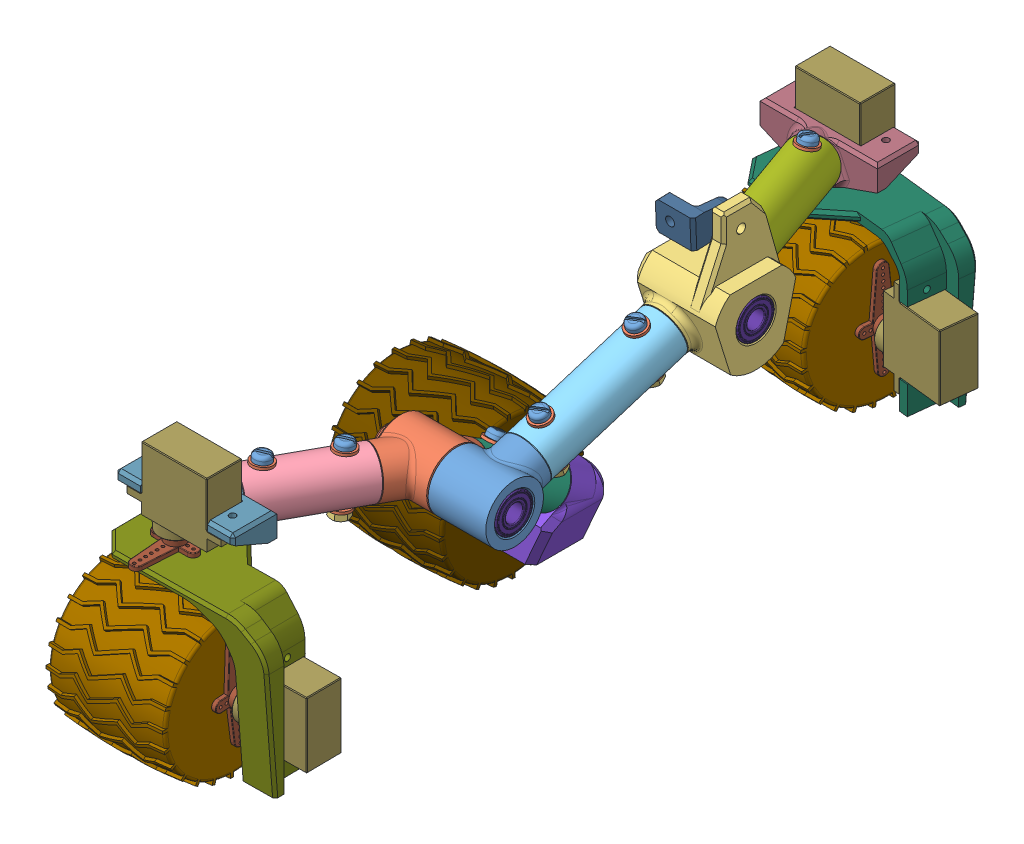
SolidWorks assembly suspensionSub-left[moving], configuration Default. Lengths in mm.
62 component instances, 21 part files, 135 mates.
Components (placement in the parent):
- bogieJointFixed-left-1: bogieJointFixed-left [Default] at (-58.6456 10.5337 84.2533) x (0 0.297904 -0.954596) z (1 0 0) size (40 20 21.53)
- bogieJointFree-left-1: bogieJointFree-left [Default] at (-79.1456 10.5337 84.2533) x (1 0 0) z (0 0.534644 0.845077) size (27.04 27.37 57.25)
- rockerJoint-left-1: rockerJoint-left [Default] at (-51.1456 34.3124 8.0574) x (1 0 0) z (0 -0.297904 0.954596) size (35.64 50.55 55.79)
- aftBogieTube-1: aftBogieTube [Default] at (-108.56 15.1077 132.4165) x (0.903071 0.263736 0.338977) z (-0.213924 0.960596 -0.177459) size (15.88 37.13 15.88)
- aftRockerTube-1: aftRockerTube [Default] at (-68.6456 15.0022 69.9343) x (1 0 0) z (0 0.954596 0.297904) size (15.88 49.82 15.88)
- foreBogieTube-1: foreBogieTube [Default] at (-89.1456 2.514 71.5771) x (0.998082 0.052308 -0.033093) z (-0.061898 0.843457 -0.533619) size (15.88 33.7 15.88)
- foreRockerTube-1: foreRockerTube [Default] at (-106.955 16.1877 -66.6715) x (0.835794 0.249633 -0.489011) z (0.320312 -0.945079 0.065011) size (15.88 70.91 15.88)
- wheelStrut-mid-right-1: wheelStrut-mid-right [Default] at (-119.2029 -30.2767 38.8726) size (23.13 36.67 28.96)
- tire-1: tire [Default] at (-113.6439 -30.2768 -79.7193) x (-0.020281 0.982539 0.184946) z (-0.994041 0 -0.109007) size (53.45 55.85 40.12)
- tire-3: tire [Default] at (-114.1463 -30.2762 146.2751) x (0.002427 0.973074 0.230481) z (-0.999945 0 0.010528) size (53.45 55.85 40.12)
- rodHinge-sus-left-1: rodHinge-sus-left [Default] at (-62.1456 34.3403 7.0424) x (0 0.33642 -0.941712) z (1 0 0) size (15.98 12.99 13)
- sg90ServoHorn-star-1: sg90ServoHorn-star [Default] at (-111.018 4.7232 -77.5199) x (0.109007 0 -0.994041) z (0.994041 0 0.109007) size (34.4 4 15.7)
- sg90ServoHorn-star-2: sg90ServoHorn-star [Default] at (-117.0162 4.7238 144.4052) x (0.010528 0 0.999945) z (-0.999945 0 0.010528) size (34.4 4 15.7)
- sg90ServoHorn-star-3: sg90ServoHorn-star [Default] at (-94.1163 -28.5447 149.0198) x (-0.000611 -0.998315 -0.058016) z (0.01051 -0.05802 0.99826) size (34.4 4 15.7)
- sg90ServoHorn-star-4: sg90ServoHorn-star [Default] at (-94.0764 -28.4129 -74.6825) x (0.001375 -0.99992 -0.012537) z (-0.108998 -0.012612 0.993962) size (34.4 4 15.7)
- sg90Servo-1: sg90Servo [Default] at (-119.8963 35.6918 140.1251) x (1 0 0) z (0 0 -1) size (32.7 29.37 12.3)
- sg90Servo-2: sg90Servo [Default] at (-63.1164 -36.0262 151.8881) x (0 1 0) z (0.010528 0 0.999945) size (32.7 29.37 12.3)
- sg90Servo-3: sg90Servo [Default] at (-63.65 -36.0268 -68.0501) x (0 1 0) z (-0.109007 0 0.994041) size (32.7 29.37 12.3)
- sg90Servo-4: sg90Servo [Default] at (-119.3939 35.6912 -85.8693) x (1 0 0) z (0 0 -1) size (32.7 29.37 12.3)
- wheelPivot-front-left-v2-1: wheelPivot-front-left-v2 [Default] at (-119.3939 35.6912 -67.5693) x (1 0 0) z (0 0 -1) size (40.7 16.47 34.17)
- wheelPivot-rear-left-v2-1: wheelPivot-rear-left-v2 [Default] at (-119.8963 35.6918 134.1251) x (-1 0 0) z (0 0 1) size (40.7 18.75 35.49)
- wheelStrut-front-left-v2-1: wheelStrut-front-left-v2 [Default] at (-64.9908 -36.0268 -55.8233) x (0 1 0) z (-0.109007 0 0.994041) size (50.75 59.16 31.22)
- wheelStrut-rear-left-v2-1: wheelStrut-rear-left-v2 [Default] at (-63.3754 -36.0262 127.2895) x (0 1 0) z (0.010528 0 0.999945) size (50.75 59.16 31.22)
- 6x13x5BearingShielded-1: 6x13x5BearingShielded [Default] at (-56.1456 34.3124 8.0574) x (0 -0.920758 0.390135) z (0 0.390135 0.920758) size (13 5 13)
- 6x13x5BearingShielded-2: 6x13x5BearingShielded [Default] at (-76.1456 34.3124 8.0574) x (0 1 0) z (0 0 1) size (13 5 13)
- 6x13x5BearingShielded-3: 6x13x5BearingShielded [Default] at (-73.6456 10.5337 84.2533) x (0 1 0) z (0 0 1) size (13 5 13)
- 6x13x5BearingShielded-4: 6x13x5BearingShielded [Default] at (-63.6456 10.5337 84.2533) x (0 -1 0) z (0 0 1) size (13 5 13)
- tire-mid-1: tire-mid [Default] at (-125.1743 -30.2767 38.8726) x (0 0.956404 0.292046) z (-1 0 0) size (53.45 55.85 40.12)
- 6x13x5BearingShielded-5: 6x13x5BearingShielded [Default] at (-110.1743 -30.2767 38.8726) x (0 -1 0) z (0 0 1) size (13 5 13)
- 6x13x5BearingShielded-6: 6x13x5BearingShielded [Default] at (-135.1743 -30.2767 38.8726) x (0 -1 0) z (0 0 1) size (13 5 13)
- pan slot head_am-1: pan slot head_am [B18.6.7M - M3 x 0.5 x 20 Slotted PHMS --20N] at (-78.6789 40.4888 -14.1636) x (0 -0.971825 0.235705) z (-0.916222 0.09444 0.389383) size (22.4 5.6 5.6)
- pan slot head_am-2: pan slot head_am [B18.6.7M - M3 x 0.5 x 20 Slotted PHMS --20N] at (-103.6106 28.6933 -62.7969) x (0 -0.971825 0.235705) z (0.226456 -0.229581 -0.946578) size (22.4 5.6 5.6)
- flat washer narrow_am-1: flat washer narrow_am [B18.22M - Plain washer, 3 mm, narrow] at (-78.6789 37.2818 -13.3857) x (0 -0.971825 0.235705) z (-0.235705 0.229064 0.944443) size (0.9 7 7)
- flat washer narrow_am-2: flat washer narrow_am [B18.22M - Plain washer, 3 mm, narrow] at (-103.6106 25.4863 -62.0191) x (0 -0.971825 0.235705) z (-0.235705 0.229064 0.944443) size (0.9 7 7)
- flat washer narrow_am-5: flat washer narrow_am [B18.22M - Plain washer, 3 mm, narrow] at (-78.6789 21.8492 -9.6427) x (0 0.971825 -0.235705) z (0.235705 0.229064 0.944443) size (0.9 7 7)
- hex nut style 1_am-1: hex nut style 1_am [B18.2.4.1M - Hex nut, Style 1,  M3 x 0.5 --D-N] at (-78.6789 18.6422 -8.8649) x (0.947171 -0.075597 -0.311692) z (0 -0.971825 0.235705) size (5.5 6.35 2.4)
- flat washer narrow_am-6: flat washer narrow_am [B18.22M - Plain washer, 3 mm, narrow] at (-103.6106 10.0537 -58.2761) x (0 0.971825 -0.235705) z (0.235705 0.229064 0.944443) size (0.9 7 7)
- hex nut style 1_am-2: hex nut style 1_am [B18.2.4.1M - Hex nut, Style 1,  M3 x 0.5 --D-N] at (-103.6106 6.8467 -57.4983) x (0.335079 0.222079 0.915644) z (0 -0.971825 0.235705) size (5.5 6.35 2.4)
- pan slot head_am-3: pan slot head_am [B18.6.7M - M3 x 0.5 x 20 Slotted PHMS --20N] at (-68.6456 38.3392 32.8843) x (0 -0.954596 -0.297904) z (-0.916222 -0.119362 0.38248) size (22.4 5.6 5.6)
- flat washer narrow_am-8: flat washer narrow_am [B18.22M - Plain washer, 3 mm, narrow] at (-68.6456 19.1709 26.9024) x (0 -0.954596 -0.297904) z (-0.235705 -0.289511 0.9277) size (0.9 7 7)
- flat washer narrow_am-9: flat washer narrow_am [B18.22M - Plain washer, 3 mm, narrow] at (-68.6456 36.0481 32.1693) x (0 0.954596 0.297904) z (0.235705 -0.289511 0.9277) size (0.9 7 7)
- hex nut style 1_am-3: hex nut style 1_am [B18.2.4.1M - Hex nut, Style 1,  M3 x 0.5 --D-N] at (-68.6456 16.8799 26.1874) x (0.947171 0.095546 -0.306166) z (0 -0.954596 -0.297904) size (5.5 6.35 2.4)
- pan slot head_am-4: pan slot head_am [B18.6.7M - M3 x 0.5 x 20 Slotted PHMS --20N] at (-68.6456 27.9662 66.1233) x (0 -0.954596 -0.297904) z (-0.916222 -0.119362 0.38248) size (22.4 5.6 5.6)
- flat washer narrow_am-10: flat washer narrow_am [B18.22M - Plain washer, 3 mm, narrow] at (-68.6456 8.7979 60.1414) x (0 -0.954596 -0.297904) z (-0.235705 -0.289511 0.9277) size (0.9 7 7)
- flat washer narrow_am-11: flat washer narrow_am [B18.22M - Plain washer, 3 mm, narrow] at (-68.6456 25.6751 65.4083) x (0 0.954596 0.297904) z (0.235705 -0.289511 0.9277) size (0.9 7 7)
- hex nut style 1_am-4: hex nut style 1_am [B18.2.4.1M - Hex nut, Style 1,  M3 x 0.5 --D-N] at (-68.6456 6.5068 59.4264) x (0.947171 0.095546 -0.306166) z (0 -0.954596 -0.297904) size (5.5 6.35 2.4)
- pan slot head_am-6: pan slot head_am [B18.6.7M - M3 x 0.5 x 20 Slotted PHMS --20N] at (-89.1456 -1.995 43.4267) x (0 -0.845077 0.534644) z (-0.916222 0.214217 0.338599) size (22.4 5.6 5.6)
- flat washer narrow_am-14: flat washer narrow_am [B18.22M - Plain washer, 3 mm, narrow] at (-89.1456 -18.9642 54.1623) x (0 -0.845077 0.534644) z (-0.235705 0.519581 0.821267) size (0.9 7 7)
- flat washer narrow_am-15: flat washer narrow_am [B18.22M - Plain washer, 3 mm, narrow] at (-89.1456 -4.0232 44.7098) x (0 0.845077 -0.534644) z (0.235705 0.519581 0.821267) size (0.9 7 7)
- hex nut style 1_am-6: hex nut style 1_am [B18.2.4.1M - Hex nut, Style 1,  M3 x 0.5 --D-N] at (-89.1456 -20.9924 55.4455) x (0.947171 -0.171476 -0.27104) z (0 -0.845077 0.534644) size (5.5 6.35 2.4)
- flat washer narrow_am-20: flat washer narrow_am [B18.22M - Plain washer, 3 mm, narrow] at (-89.1456 -8.9663 69.9653) x (0 -0.845077 0.534644) z (-0.235705 0.519581 0.821267) size (0.9 7 7)
- flat washer narrow_am-21: flat washer narrow_am [B18.22M - Plain washer, 3 mm, narrow] at (-89.1456 5.9746 60.5128) x (0 0.845077 -0.534644) z (0.235705 0.519581 0.821267) size (0.9 7 7)
- hex nut style 1_am-9: hex nut style 1_am [B18.2.4.1M - Hex nut, Style 1,  M3 x 0.5 --D-N] at (-89.1456 -10.9945 71.2484) x (0.947171 -0.171476 -0.27104) z (0 -0.845077 0.534644) size (5.5 6.35 2.4)
- pan slot head_am-9: pan slot head_am [B18.6.7M - M3 x 0.5 x 20 Slotted PHMS --20N] at (-89.1456 8.0028 59.2296) x (0 -0.845077 0.534644) z (-0.916222 0.214217 0.338599) size (22.4 5.6 5.6)
- flat washer narrow_am-22: flat washer narrow_am [B18.22M - Plain washer, 3 mm, narrow] at (-97.5251 3.7075 105.8769) x (0 -0.995521 0.094544) z (-0.195476 0.09272 0.976316) size (0.9 7 7)
- flat washer narrow_am-23: flat washer narrow_am [B18.22M - Plain washer, 3 mm, narrow] at (-97.5251 21.3083 104.2054) x (0 0.995521 -0.094544) z (0.275533 0.090884 0.956986) size (0.9 7 7)
- hex nut style 1_am-10: hex nut style 1_am [B18.2.4.1M - Hex nut, Style 1,  M3 x 0.5 --D-N] at (-97.5251 1.3182 106.1038) x (0.933157 -0.033986 -0.35786) z (0 -0.995521 0.094544) size (5.5 6.35 2.4)
- pan slot head_am-10: pan slot head_am [B18.6.7M - M3 x 0.5 x 20 Slotted PHMS --20N] at (-97.5251 23.6975 103.9785) x (0 -0.995521 0.094544) z (-0.898941 0.041417 0.436108) size (22.4 5.6 5.6)
- flat washer narrow_am-24: flat washer narrow_am [B18.22M - Plain washer, 3 mm, narrow] at (-105.7668 5.6492 126.323) x (0 -0.995521 0.094544) z (-0.195476 0.09272 0.976316) size (0.9 7 7)
- flat washer narrow_am-25: flat washer narrow_am [B18.22M - Plain washer, 3 mm, narrow] at (-105.7668 23.25 124.6514) x (0 0.995521 -0.094544) z (0.275533 0.090884 0.956986) size (0.9 7 7)
- hex nut style 1_am-11: hex nut style 1_am [B18.2.4.1M - Hex nut, Style 1,  M3 x 0.5 --D-N] at (-105.7668 3.26 126.5499) x (0.933157 -0.033986 -0.35786) z (0 -0.995521 0.094544) size (5.5 6.35 2.4)
- pan slot head_am-11: pan slot head_am [B18.6.7M - M3 x 0.5 x 20 Slotted PHMS --20N] at (-105.7668 25.6393 124.4245) x (0 -0.995521 0.094544) z (-0.898941 0.041417 0.436108) size (22.4 5.6 5.6)
Mates (geometry in assembly coordinates):
- Parallel1: parallel aligned: plane of rockerJoint-left-1 through (-81.1466 46.3124 8.0574) normal (0 1 0); plane of assembly through (0 0 0) normal (0 1 0)
- Concentric3: concentric aligned: line of rockerJoint-left-1 through (-68.6456 34.3124 8.0574) axis (-0.445925 -0.210972 -0.869851); cylinder of foreRockerTube-1 through (-75.3345 31.1478 -4.9903) axis (-0.445925 -0.210972 -0.869851) radius 7.94
- Coincident4: coincident anti-aligned: plane of rockerJoint-left-1 through (-75.3345 31.1478 -4.9903) normal (-0.445925 -0.210972 -0.869851); plane of foreRockerTube-1 through (-75.3345 31.1478 -4.9903) normal (0.445925 0.210972 0.869851)
- Concentric4: concentric anti-aligned: line of rockerJoint-left-1 through (-68.6456 9.9222 86.2125) axis (0 0.297904 -0.954596); cylinder of aftRockerTube-1 through (-68.6456 29.8438 22.3764) axis (0 -0.297904 0.954596) radius 7.94
- Coincident5: coincident anti-aligned: plane of rockerJoint-left-1 through (-68.6456 29.8438 22.3764) normal (0 -0.297904 0.954596); plane of aftRockerTube-1 through (-68.6456 29.8438 22.3764) normal (0 0.297904 -0.954596)
- Concentric5: concentric aligned: line of bogieJointFixed-left-1 through (-68.6456 15.0022 69.9343) axis (0 -0.297904 0.954596); cylinder of aftRockerTube-1 through (-68.6456 29.8438 22.3764) axis (0 -0.297904 0.954596) radius 7.94
- Coincident6: coincident anti-aligned: plane of bogieJointFixed-left-1 through (-68.6456 15.0022 69.9343) normal (0 0.297904 -0.954596); plane of aftRockerTube-1 through (-68.6456 15.0022 69.9343) normal (0 -0.297904 0.954596)
- Concentric6: concentric anti-aligned: line of bogieJointFree-left-1 through (-89.1456 10.5337 84.2533) axis (0 -0.534644 -0.845077); cylinder of foreBogieTube-1 through (-89.1456 -15.5035 43.098) axis (0 0.534644 0.845077) radius 7.94
- Coincident9: coincident anti-aligned: plane of bogieJointFree-left-1 through (-89.1456 2.514 71.5771) normal (0 -0.534644 -0.845077); plane of foreBogieTube-1 through (-89.1456 2.514 71.5771) normal (0 0.534644 0.845077)
- Concentric8: concentric anti-aligned: line of bogieJointFree-left-1 through (-114.1456 16.4237 146.2733) axis (0.372423 -0.087743 -0.923906); cylinder of aftBogieTube-1 through (-94.732 11.8498 98.1119) axis (-0.372423 0.087743 0.923906) radius 7.94
- Coincident11: coincident anti-aligned: plane of bogieJointFree-left-1 through (-94.732 11.8498 98.1119) normal (-0.372423 0.087743 0.923906); plane of aftBogieTube-1 through (-94.732 11.8498 98.1119) normal (0.372423 -0.087743 -0.923906)
- Concentric12: concentric anti-aligned: cylinder of foreBogieTube-1 through (-89.1456 -15.5035 43.098) axis (0 0.534644 0.845077) radius 7.94; line of wheelStrut-mid-right-1 through (-89.1456 10.5333 84.2526) axis (0 -0.534644 -0.845077)
- Coincident14: coincident anti-aligned: plane of foreBogieTube-1 through (-89.1456 -15.5035 43.098) normal (0 -0.534644 -0.845077); plane of wheelStrut-mid-right-1 through (-89.1456 -15.5035 43.098) normal (0 0.534644 0.845077)
- Distance6: distance = 1 mm anti-aligned: plane of rockerJoint-left-1 through (-61.1456 40.2303 22.2025) normal (-1 0 0); plane of rodHinge-sus-left-1 through (-62.1456 34.3403 7.0424) normal (1 0 0)
- Concentric18: concentric anti-aligned: cylinder of rockerJoint-left-1 through (-51.1446 59.3124 8.2384) axis (-1 0 0) radius 1.55; cylinder of rodHinge-sus-left-1 through (-65.1456 59.3124 8.2384) axis (1 0 0) radius 1.55
- Concentric20: concentric aligned: cylinder of foreRockerTube-1 through (-75.3345 31.1478 -4.9903) axis (-0.445925 -0.210972 -0.869851) radius 7.94; cylinder of wheelPivot-front-left-v2-1 through (-106.955 16.1877 -66.6715) axis (-0.445925 -0.210972 -0.869851) radius 7.94
- Coincident46: coincident anti-aligned: plane of foreRockerTube-1 through (-106.955 16.1877 -66.6715) normal (-0.445925 -0.210972 -0.869851); plane of wheelPivot-front-left-v2-1 through (-106.955 16.1877 -66.6715) normal (0.445925 0.210972 0.869851)
- Parallel2: parallel aligned: plane of rockerJoint-left-1 through (-81.1466 46.3124 8.0574) normal (0 1 0); plane of wheelPivot-front-left-v2-1 through (-119.3939 23.0662 -70.5693) normal (0 1 0)
- Coincident48: coincident aligned: line of sg90Servo-4 through (-96.4439 20.0662 -85.6193) axis (0 0 1); line of wheelPivot-front-left-v2-1 through (-96.4439 20.0662 -85.8693) axis (0 0 1)
- Coincident49: coincident anti-aligned: line of sg90Servo-4 through (-119.6439 20.0662 -73.8193) axis (0 0 -1); line of wheelPivot-front-left-v2-1 through (-119.6439 20.0662 -85.8693) axis (0 0 1)
- Coincident50: coincident anti-aligned: plane of sg90Servo-4 through (-119.3939 13.4662 -73.5693) normal (0 0 1); plane of wheelPivot-front-left-v2-1 through (-119.3939 35.6912 -73.5693) normal (0 0 -1)
- Concentric21: concentric aligned: cylinder of aftBogieTube-1 through (-94.732 11.8498 98.1119) axis (-0.372423 0.087743 0.923906) radius 7.94; cylinder of wheelPivot-rear-left-v2-1 through (-108.56 15.1077 132.4165) axis (-0.372423 0.087743 0.923906) radius 7.94
- Coincident51: coincident anti-aligned: plane of aftBogieTube-1 through (-108.56 15.1077 132.4165) normal (-0.372423 0.087743 0.923906); plane of wheelPivot-rear-left-v2-1 through (-108.56 15.1077 132.4165) normal (0.372423 -0.087743 -0.923906)
- Coincident53: coincident aligned: line of sg90Servo-1 through (-120.1463 20.0668 152.1751) axis (0 0 -1); line of wheelPivot-rear-left-v2-1 through (-120.1463 20.0668 152.4251) axis (0 0 -1)
- Coincident54: coincident anti-aligned: line of sg90Servo-1 through (-96.9463 20.0668 140.3751) axis (0 0 1); line of wheelPivot-rear-left-v2-1 through (-96.9463 20.0668 152.4251) axis (0 0 -1)
- Coincident55: coincident anti-aligned: plane of sg90Servo-1 through (-119.8963 13.4668 140.1251) normal (0 0 -1); plane of wheelPivot-rear-left-v2-1 through (-119.8963 35.6918 140.1251) normal (0 0 1)
- Coincident56: coincident anti-aligned: plane of sg90ServoHorn-star-1 through (-111.018 4.7232 -77.5199) normal (0 -1 0); plane of wheelStrut-front-left-v2-1 through (-61.5462 4.7232 -87.235) normal (0 1 0)
- Concentric22: concentric aligned: cylinder of sg90ServoHorn-star-1 through (-113.6439 4.7222 -79.7193) axis (0 1 0) radius 1.2; cylinder of wheelStrut-front-left-v2-1 through (-113.6439 -46.0279 -79.7193) axis (0 1 0) radius 2.4
- Coincident58: coincident anti-aligned: plane of sg90ServoHorn-star-2 through (-117.0162 4.7238 144.4052) normal (0 -1 0); plane of wheelStrut-rear-left-v2-1 through (-63.0427 4.7238 158.8878) normal (0 1 0)
- Concentric23: concentric aligned: cylinder of sg90ServoHorn-star-2 through (-114.1463 4.7228 146.2751) axis (0 1 0) radius 1.2; cylinder of wheelStrut-rear-left-v2-1 through (-114.1463 -46.0272 146.2751) axis (0 1 0) radius 2.4
- Concentric24: concentric aligned: cylinder of sg90ServoHorn-star-1 through (-113.6439 6.3232 -79.7193) axis (0 1 0) radius 2.4; cylinder of sg90Servo-4 through (-113.6439 6.3232 -79.7193) axis (0 1 0) radius 1.984
- Coincident60: coincident anti-aligned: plane of sg90ServoHorn-star-1 through (-113.6439 6.3232 -79.7193) normal (0 1 0); plane of sg90Servo-4 through (-113.6439 6.3232 -79.7193) normal (0 -1 0)
- Concentric25: concentric aligned: cylinder of sg90ServoHorn-star-2 through (-114.1463 6.3238 146.2751) axis (0 1 0) radius 2.4; cylinder of sg90Servo-1 through (-114.1463 6.3238 146.2751) axis (0 1 0) radius 1.984
- Coincident61: coincident anti-aligned: plane of sg90ServoHorn-star-2 through (-114.1463 6.3238 146.2751) normal (0 1 0); plane of sg90Servo-1 through (-114.1463 6.3238 146.2751) normal (0 -1 0)
- Coincident63: coincident anti-aligned: plane of tire-3 through (-94.0892 -6.9248 151.5955) normal (0.999945 0 -0.010528); plane of sg90ServoHorn-star-3 through (-94.1163 -28.5447 149.0198) normal (-0.999945 0 0.010528)
- Concentric26: concentric anti-aligned: line of tire-3 through (-92.1476 -30.2762 146.0435) axis (-0.999945 0 0.010528); cylinder of sg90ServoHorn-star-3 through (-94.1485 -30.2762 146.0645) axis (0.999945 0 -0.010528) radius 1.2
- Coincident64: coincident anti-aligned: line of sg90Servo-2 through (-78.7432 -13.0762 151.8027) axis (-0.010528 0 -0.999945); line of wheelStrut-rear-left-v2-1 through (-78.8701 -13.0762 139.7533) axis (0.010528 0 0.999945)
- Coincident65: coincident aligned: line of sg90Servo-2 through (-78.8674 -36.2762 140.0033) axis (0.010528 0 0.999945); line of wheelStrut-rear-left-v2-1 through (-78.8701 -36.2762 139.7533) axis (0.010528 0 0.999945)
- Coincident66: coincident anti-aligned: plane of sg90Servo-2 through (-85.3402 -36.0262 152.1221) normal (0.010528 0 0.999945); plane of wheelStrut-rear-left-v2-1 through (-63.1164 -36.0262 151.8881) normal (-0.010528 0 -0.999945)
- Concentric28: concentric aligned: cylinder of sg90ServoHorn-star-3 through (-92.5475 -30.2762 146.0477) axis (0.999945 0 -0.010528) radius 2.4; cylinder of sg90Servo-2 through (-92.5475 -30.2762 146.0477) axis (0.999945 0 -0.010528) radius 1.984
- Coincident67: coincident anti-aligned: plane of sg90ServoHorn-star-3 through (-92.5475 -30.2762 146.0477) normal (0.999945 0 -0.010528); plane of sg90Servo-2 through (-92.5475 -30.2762 146.0477) normal (-0.999945 0 0.010528)
- Coincident68: coincident anti-aligned: plane of tire-1 through (-94.2498 -6.6984 -73.1009) normal (0.994041 0 0.109007); plane of sg90ServoHorn-star-4 through (-94.0764 -28.4129 -74.6825) normal (-0.994041 0 -0.109007)
- Concentric30: concentric anti-aligned: line of tire-1 through (-91.775 -30.2768 -77.3211) axis (-0.994041 0 -0.109007); cylinder of sg90ServoHorn-star-4 through (-93.7641 -30.2768 -77.5392) axis (0.994041 0 0.109007) radius 1.2
- Coincident69: coincident aligned: line of sg90Servo-3 through (-79.1547 -13.0768 -70.0018) axis (0.109007 0 -0.994041); line of wheelStrut-front-left-v2-1 through (-79.1819 -13.0768 -69.7533) axis (0.109007 0 -0.994041)
- Coincident70: coincident anti-aligned: line of sg90Servo-3 through (-77.8684 -36.2768 -81.7315) axis (-0.109007 0 0.994041); line of wheelStrut-front-left-v2-1 through (-79.1819 -36.2768 -69.7533) axis (0.109007 0 -0.994041)
- Coincident71: coincident anti-aligned: plane of sg90Servo-3 through (-84.4018 -36.0268 -82.6994) normal (0.109007 0 -0.994041); plane of wheelStrut-front-left-v2-1 through (-62.3092 -36.0268 -80.2768) normal (-0.109007 0 0.994041)
- Concentric33: concentric aligned: cylinder of sg90ServoHorn-star-4 through (-92.1726 -30.2768 -77.3647) axis (0.994041 0 0.109007) radius 2.4; cylinder of sg90Servo-3 through (-92.1726 -30.2768 -77.3647) axis (0.994041 0 0.109007) radius 1.984
- Coincident72: coincident anti-aligned: plane of sg90ServoHorn-star-4 through (-92.1726 -30.2768 -77.3647) normal (0.994041 0 0.109007); plane of sg90Servo-3 through (-92.1726 -30.2768 -77.3647) normal (-0.994041 0 -0.109007)
- Concentric34: concentric anti-aligned: cylinder of rockerJoint-left-1 through (-75.1456 34.3124 8.0574) axis (-1 0 0) radius 6.5; cylinder of 6x13x5BearingShielded-2 through (-81.1456 34.3124 8.0574) axis (1 0 0) radius 6.5
- Coincident73: coincident aligned: plane of rockerJoint-left-1 through (-81.1456 34.3124 8.0574) normal (-1 0 0); plane of 6x13x5BearingShielded-2 through (-81.1456 34.3124 8.0574) normal (-1 0 0)
- Concentric35: concentric anti-aligned: cylinder of rockerJoint-left-1 through (-57.1456 34.3124 8.0574) axis (1 0 0) radius 6.5; cylinder of 6x13x5BearingShielded-1 through (-51.1456 34.3124 8.0574) axis (-1 0 0) radius 6.5
- Coincident74: coincident aligned: plane of rockerJoint-left-1 through (-51.1456 34.3124 8.0574) normal (1 0 0); plane of 6x13x5BearingShielded-1 through (-51.1456 34.3124 8.0574) normal (1 0 0)
- Concentric37: concentric anti-aligned: cylinder of bogieJointFixed-left-1 through (-64.6456 10.5337 84.2533) axis (1 0 0) radius 6.5; cylinder of 6x13x5BearingShielded-4 through (-58.6456 10.5337 84.2533) axis (-1 0 0) radius 6.5
- Coincident75: coincident aligned: plane of bogieJointFixed-left-1 through (-58.6456 10.5337 84.2533) normal (1 0 0); plane of 6x13x5BearingShielded-4 through (-58.6456 10.5337 84.2533) normal (1 0 0)
- Concentric38: concentric anti-aligned: cylinder of bogieJointFixed-left-1 through (-72.6456 10.5337 84.2533) axis (-1 0 0) radius 6.5; cylinder of 6x13x5BearingShielded-3 through (-78.6456 10.5337 84.2533) axis (1 0 0) radius 6.5
- Coincident76: coincident aligned: plane of bogieJointFixed-left-1 through (-78.6456 10.5337 84.2533) normal (-1 0 0); plane of 6x13x5BearingShielded-3 through (-78.6456 10.5337 84.2533) normal (-1 0 0)
- Concentric39: concentric aligned: cylinder of bogieJointFixed-left-1 through (-78.6456 10.5337 84.2533) axis (1 0 0) radius 10; cylinder of bogieJointFree-left-1 through (-99.1456 10.5337 84.2533) axis (1 0 0) radius 10
- Distance7: distance = 0.5 mm anti-aligned: plane of bogieJointFree-left-1 through (-79.1456 10.5337 84.2533) normal (1 0 0); plane of bogieJointFixed-left-1 through (-78.6456 10.5337 84.2533) normal (-1 0 0)
- Concentric40: concentric aligned: cylinder of wheelStrut-mid-right-1 through (-76.2571 -30.2767 38.8726) axis (-1 0 0) radius 3; cylinder of tire-mid-1 through (-105.1146 -30.2767 38.8726) axis (-1 0 0) radius 3.75
- Distance8: distance = 1 mm anti-aligned: plane of tire-mid-1 through (-105.1743 -7.3254 45.881) normal (1 0 0); plane of wheelStrut-mid-right-1 through (-104.1743 -30.2767 48.8726) normal (-1 0 0)
- Concentric41: concentric anti-aligned: cylinder of tire-mid-1 through (-111.1743 -30.2767 38.8726) axis (1 0 0) radius 6.5; cylinder of 6x13x5BearingShielded-5 through (-105.1743 -30.2767 38.8726) axis (-1 0 0) radius 6.5
- Coincident79: coincident aligned: plane of tire-mid-1 through (-105.1743 -7.3254 45.881) normal (1 0 0); plane of 6x13x5BearingShielded-5 through (-105.1743 -30.2767 38.8726) normal (1 0 0)
- Concentric42: concentric aligned: cylinder of tire-mid-1 through (-129.1743 -30.2767 38.8726) axis (-1 0 0) radius 6.5; cylinder of 6x13x5BearingShielded-6 through (-130.1743 -30.2767 38.8726) axis (-1 0 0) radius 6.5
- Coincident80: coincident aligned: plane of tire-mid-1 through (-135.1743 -30.2767 38.8726) normal (-1 0 0); plane of 6x13x5BearingShielded-6 through (-135.1743 -30.2767 38.8726) normal (-1 0 0)
- Concentric45: concentric aligned: cylinder of tire-3 through (-104.5519 -15.3014 147.0444) axis (0.999945 0 -0.010528) radius 0.5; cylinder of sg90ServoHorn-star-3 through (-94.1393 -15.3014 146.9348) axis (0.999945 0 -0.010528) radius 0.5
- Concentric46: concentric aligned: cylinder of tire-1 through (-104.1359 -15.278 -78.4863) axis (0.994041 0 0.109007) radius 0.5; cylinder of sg90ServoHorn-star-4 through (-93.7847 -15.278 -77.3512) axis (0.994041 0 0.109007) radius 0.5
- Concentric47: concentric aligned: cylinder of sg90ServoHorn-star-2 through (-114.2411 4.7228 137.2756) axis (0 1 0) radius 0.5; cylinder of wheelStrut-rear-left-v2-1 through (-114.2411 -46.0272 137.2756) axis (0 1 0) radius 0.5
- Concentric48: concentric aligned: cylinder of sg90ServoHorn-star-1 through (-114.625 4.7222 -70.7729) axis (0 1 0) radius 0.5; cylinder of wheelStrut-front-left-v2-1 through (-114.625 -46.0279 -70.7729) axis (0 1 0) radius 0.5
- Concentric49: concentric anti-aligned: cylinder of rockerJoint-left-1 through (-78.6789 -0.8192 -4.1448) axis (0 0.971825 -0.235705) radius 1.55; cylinder of foreRockerTube-1 through (-78.6789 39.5321 -13.9315) axis (0 -0.971825 0.235705) radius 1.55
- Concentric52: concentric anti-aligned: cylinder of rockerJoint-left-1 through (-68.6456 9.987 24.0363) axis (0 0.954596 0.297904) radius 1.55; cylinder of aftRockerTube-1 through (-68.6458 35.189 31.9012) axis (0 -0.954596 -0.297904) radius 1.55
- Concentric71: concentric aligned: cylinder of pan slot head_am-1 through (-78.6789 65.1731 -20.1504) axis (0 0.971825 -0.235705) radius 1.5; cylinder of flat washer narrow_am-1 through (-78.6789 71.2228 -21.6177) axis (0 0.971825 -0.235705) radius 1.84
- Concentric721: concentric anti-aligned: cylinder of foreRockerTube-1 through (-78.6789 39.5321 -13.9315) axis (0 -0.971825 0.235705) radius 1.55; cylinder of pan slot head_am-1 through (-78.6789 65.1731 -20.1504) axis (0 0.971825 -0.235705) radius 1.5
- Coincident831: coincident anti-aligned: plane of pan slot head_am-1 through (-78.0779 38.4804 -12.2623) normal (0 -0.971825 0.235705); plane of flat washer narrow_am-1 through (-75.2775 38.3509 -12.7961) normal (0 0.971825 -0.235705)
- Concentric73: concentric aligned: cylinder of pan slot head_am-2 through (-103.6106 53.3777 -68.7838) axis (0 0.971825 -0.235705) radius 1.5; cylinder of flat washer narrow_am-2 through (-103.6106 59.4273 -70.2511) axis (0 0.971825 -0.235705) radius 1.84
- Concentric741: concentric anti-aligned: cylinder of foreRockerTube-1 through (-103.6106 27.7367 -62.5649) axis (0 -0.971825 0.235705) radius 1.55; cylinder of pan slot head_am-2 through (-103.6106 53.3777 -68.7838) axis (0 0.971825 -0.235705) radius 1.5
- Coincident841: coincident anti-aligned: plane of pan slot head_am-2 through (-105.0716 26.2809 -62.5614) normal (0 -0.971825 0.235705); plane of flat washer narrow_am-2 through (-100.2092 26.5554 -61.4295) normal (0 0.971825 -0.235705)
- Concentric77: concentric anti-aligned: cylinder of pan slot head_am-1 through (-78.6789 65.1731 -20.1504) axis (0 0.971825 -0.235705) radius 1.5; cylinder of flat washer narrow_am-5 through (-78.6789 -12.0918 -1.4108) axis (0 -0.971825 0.235705) radius 1.84
- Concentric78: concentric anti-aligned: cylinder of pan slot head_am-1 through (-78.6789 65.1731 -20.1504) axis (0 0.971825 -0.235705) radius 1.5; cylinder of hex nut style 1_am-1 through (-78.6789 42.9742 -14.7664) axis (0 -0.971825 0.235705) radius 1.5
- Coincident85: coincident anti-aligned: plane of flat washer narrow_am-5 through (-82.0803 21.169 -8.6289) normal (0 -0.971825 0.235705); plane of hex nut style 1_am-1 through (-77.6605 21.6835 -6.5077) normal (0 0.971825 -0.235705)
- Concentric79: concentric anti-aligned: cylinder of pan slot head_am-2 through (-103.6106 53.3777 -68.7838) axis (0 0.971825 -0.235705) radius 1.5; cylinder of flat washer narrow_am-6 through (-103.6106 -23.8872 -50.0441) axis (0 -0.971825 0.235705) radius 1.84
- Concentric80: concentric anti-aligned: cylinder of pan slot head_am-2 through (-103.6106 53.3777 -68.7838) axis (0 0.971825 -0.235705) radius 1.5; cylinder of hex nut style 1_am-2 through (-103.6106 31.1788 -63.3998) axis (0 -0.971825 0.235705) radius 1.5
- Coincident86: coincident anti-aligned: plane of flat washer narrow_am-6 through (-107.012 9.3736 -57.2623) normal (0 -0.971825 0.235705); plane of hex nut style 1_am-2 through (-106.6025 9.4299 -57.03) normal (0 0.971825 -0.235705)
- Tangent1: tangent anti-aligned: cylinder of foreRockerTube-1 through (-75.3345 31.1478 -4.9903) axis (-0.445925 -0.210972 -0.869851) radius 7.94; plane of flat washer narrow_am-2 through (-101.8224 25.5885 -61.5976) normal (0 -0.971825 0.235705)
- Tangent2: tangent anti-aligned: cylinder of foreRockerTube-1 through (-75.3345 31.1478 -4.9903) axis (-0.445925 -0.210972 -0.869851) radius 7.94; plane of flat washer narrow_am-6 through (-105.3988 10.156 -57.8547) normal (0 0.971825 -0.235705)
- Tangent3: tangent anti-aligned: cylinder of foreRockerTube-1 through (-75.3345 31.1478 -4.9903) axis (-0.445925 -0.210972 -0.869851) radius 7.94; plane of flat washer narrow_am-1 through (-76.8908 37.384 -12.9643) normal (0 -0.971825 0.235705)
- Tangent4: tangent anti-aligned: cylinder of foreRockerTube-1 through (-75.3345 31.1478 -4.9903) axis (-0.445925 -0.210972 -0.869851) radius 7.94; plane of flat washer narrow_am-5 through (-80.4671 21.9514 -9.2213) normal (0 0.971825 -0.235705)
- Concentric83: concentric anti-aligned: cylinder of pan slot head_am-3 through (-68.6456 62.5859 40.451) axis (0 0.954596 0.297904) radius 1.5; cylinder of flat washer narrow_am-9 through (-68.6456 2.7089 21.765) axis (0 -0.954596 -0.297904) radius 1.84
- Coincident90: coincident anti-aligned: plane of pan slot head_am-3 through (-68.0446 35.6387 33.4812) normal (0 -0.954596 -0.297904); plane of flat washer narrow_am-9 through (-70.4338 35.9189 32.5833) normal (0 0.954596 0.297904)
- Concentric84: concentric aligned: cylinder of pan slot head_am-3 through (-68.6456 62.5859 40.451) axis (0 0.954596 0.297904) radius 1.5; cylinder of flat washer narrow_am-8 through (-68.6456 52.5102 37.3067) axis (0 0.954596 0.297904) radius 1.84
- Concentric85: concentric anti-aligned: cylinder of pan slot head_am-3 through (-68.6456 62.5859 40.451) axis (0 0.954596 0.297904) radius 1.5; cylinder of hex nut style 1_am-3 through (-68.6456 19.1709 26.9024) axis (0 -0.954596 -0.297904) radius 1.25
- Coincident91: coincident anti-aligned: plane of flat washer narrow_am-8 through (-66.8575 19.0417 27.3164) normal (0 -0.954596 -0.297904); plane of hex nut style 1_am-3 through (-67.6272 18.2749 29.7735) normal (0 0.954596 0.297904)
- Concentric86: concentric aligned: cylinder of rockerJoint-left-1 through (-68.6456 9.987 24.0363) axis (0 0.954596 0.297904) radius 1.55; cylinder of pan slot head_am-3 through (-68.6456 62.5859 40.451) axis (0 0.954596 0.297904) radius 1.5
- Tangent5: tangent anti-aligned: cylinder of aftRockerTube-1 through (-68.6456 29.8438 22.3764) axis (0 -0.297904 0.954596) radius 7.94; plane of flat washer narrow_am-9 through (-72.047 34.9432 32.6887) normal (0 -0.954596 -0.297904)
- Tangent6: tangent anti-aligned: cylinder of aftRockerTube-1 through (-68.6456 29.8438 22.3764) axis (0 -0.297904 0.954596) radius 7.94; plane of flat washer narrow_am-8 through (-65.2442 19.7843 27.958) normal (0 0.954596 0.297904)
- Concentric742: concentric anti-aligned: cylinder of bogieJointFixed-left-1 through (-68.6456 7.6896 59.7955) axis (0 0.954596 0.297904) radius 1.55; cylinder of aftRockerTube-1 through (-68.6458 24.816 65.1402) axis (0 -0.954596 -0.297904) radius 1.55
- Concentric743: concentric anti-aligned: cylinder of pan slot head_am-4 through (-68.6456 52.2129 73.6901) axis (0 0.954596 0.297904) radius 1.5; cylinder of flat washer narrow_am-11 through (-68.6456 -7.6641 55.004) axis (0 -0.954596 -0.297904) radius 1.84
- Coincident842: coincident anti-aligned: plane of pan slot head_am-4 through (-68.0446 25.2657 66.7203) normal (0 -0.954596 -0.297904); plane of flat washer narrow_am-11 through (-70.4338 25.5459 65.8223) normal (0 0.954596 0.297904)
- Concentric744: concentric aligned: cylinder of pan slot head_am-4 through (-68.6456 52.2129 73.6901) axis (0 0.954596 0.297904) radius 1.5; cylinder of flat washer narrow_am-10 through (-68.6456 42.1371 70.5457) axis (0 0.954596 0.297904) radius 1.84
- Concentric745: concentric anti-aligned: cylinder of pan slot head_am-4 through (-68.6456 52.2129 73.6901) axis (0 0.954596 0.297904) radius 1.5; cylinder of hex nut style 1_am-4 through (-68.6456 8.7979 60.1414) axis (0 -0.954596 -0.297904) radius 1.25
- Coincident843: coincident anti-aligned: plane of flat washer narrow_am-10 through (-66.8575 8.6687 60.5554) normal (0 -0.954596 -0.297904); plane of hex nut style 1_am-4 through (-67.6272 7.9019 63.0125) normal (0 0.954596 0.297904)
- Tangent7: tangent anti-aligned: cylinder of aftRockerTube-1 through (-68.6456 29.8438 22.3764) axis (0 -0.297904 0.954596) radius 7.94; plane of flat washer narrow_am-11 through (-72.047 24.5702 65.9277) normal (0 -0.954596 -0.297904)
- Tangent8: tangent anti-aligned: cylinder of aftRockerTube-1 through (-68.6456 29.8438 22.3764) axis (0 -0.297904 0.954596) radius 7.94; plane of flat washer narrow_am-10 through (-65.2442 9.4112 61.197) normal (0 0.954596 0.297904)
- Concentric746: concentric aligned: cylinder of bogieJointFixed-left-1 through (-68.6456 7.6896 59.7955) axis (0 0.954596 0.297904) radius 1.55; cylinder of pan slot head_am-4 through (-68.6456 52.2129 73.6901) axis (0 0.954596 0.297904) radius 1.5
- Concentric750: concentric anti-aligned: cylinder of pan slot head_am-6 through (-89.1456 19.4699 29.8467) axis (0 0.845077 -0.534644) radius 1.5; cylinder of flat washer narrow_am-15 through (-89.1456 -33.5375 63.3823) axis (0 -0.845077 0.534644) radius 1.84
- Coincident846: coincident anti-aligned: plane of pan slot head_am-6 through (-88.5446 -3.2884 45.8712) normal (0 -0.845077 0.534644); plane of flat washer narrow_am-15 through (-90.9338 -3.7913 45.0763) normal (0 0.845077 -0.534644)
- Concentric751: concentric aligned: cylinder of pan slot head_am-6 through (-89.1456 19.4699 29.8467) axis (0 0.845077 -0.534644) radius 1.5; cylinder of flat washer narrow_am-14 through (-89.1456 10.5501 35.4899) axis (0 0.845077 -0.534644) radius 1.84
- Concentric752: concentric anti-aligned: cylinder of pan slot head_am-6 through (-89.1456 19.4699 29.8467) axis (0 0.845077 -0.534644) radius 1.5; cylinder of hex nut style 1_am-6 through (-89.1456 -18.9642 54.1623) axis (0 -0.845077 0.534644) radius 1.25
- Coincident847: coincident anti-aligned: plane of flat washer narrow_am-14 through (-87.3575 -18.7323 54.5288) normal (0 -0.845077 0.534644); plane of hex nut style 1_am-6 through (-88.1272 -17.3561 56.7041) normal (0 0.845077 -0.534644)
- Tangent11: tangent anti-aligned: cylinder of foreBogieTube-1 through (-89.1456 -15.5035 43.098) axis (0 0.534644 0.845077) radius 7.94; plane of flat washer narrow_am-15 through (-92.547 -4.3427 45.8882) normal (0 -0.845077 0.534644)
- Tangent12: tangent anti-aligned: cylinder of foreBogieTube-1 through (-89.1456 -15.5035 43.098) axis (0 0.534644 0.845077) radius 7.94; plane of flat washer narrow_am-14 through (-85.7442 -17.7625 54.3783) normal (0 0.845077 -0.534644)
- Concentric753: concentric aligned: cylinder of wheelStrut-mid-right-1 through (-89.1456 -35.8441 64.8415) axis (0 0.845077 -0.534644) radius 1.55; cylinder of pan slot head_am-6 through (-89.1456 19.4699 29.8467) axis (0 0.845077 -0.534644) radius 1.5
- Concentric762: concentric anti-aligned: cylinder of flat washer narrow_am-21 through (-89.1456 -23.5397 79.1852) axis (0 -0.845077 0.534644) radius 1.84; cylinder of pan slot head_am-9 through (-89.1456 29.4678 45.6497) axis (0 0.845077 -0.534644) radius 1.5
- Coincident855: coincident anti-aligned: plane of flat washer narrow_am-21 through (-90.9338 6.2065 60.8793) normal (0 0.845077 -0.534644); plane of pan slot head_am-9 through (-88.5446 6.7094 61.6742) normal (0 -0.845077 0.534644)
- Concentric763: concentric aligned: cylinder of flat washer narrow_am-20 through (-89.1456 20.548 51.2928) axis (0 0.845077 -0.534644) radius 1.84; cylinder of pan slot head_am-9 through (-89.1456 29.4678 45.6497) axis (0 0.845077 -0.534644) radius 1.5
- Concentric764: concentric anti-aligned: cylinder of hex nut style 1_am-9 through (-89.1456 -8.9663 69.9653) axis (0 -0.845077 0.534644) radius 1.25; cylinder of pan slot head_am-9 through (-89.1456 29.4678 45.6497) axis (0 0.845077 -0.534644) radius 1.5
- Coincident856: coincident anti-aligned: plane of flat washer narrow_am-20 through (-87.3575 -8.7344 70.3318) normal (0 -0.845077 0.534644); plane of hex nut style 1_am-9 through (-88.1272 -7.3583 72.507) normal (0 0.845077 -0.534644)
- Tangent17: tangent anti-aligned: cylinder of foreBogieTube-1 through (-89.1456 -15.5035 43.098) axis (0 0.534644 0.845077) radius 7.94; plane of flat washer narrow_am-20 through (-85.7442 -7.7647 70.1813) normal (0 0.845077 -0.534644)
- Tangent19: tangent anti-aligned: cylinder of foreBogieTube-1 through (-89.1456 -15.5035 43.098) axis (0 0.534644 0.845077) radius 7.94; plane of flat washer narrow_am-21 through (-92.547 5.6551 61.6911) normal (0 -0.845077 0.534644)
- Concentric766: concentric aligned: cylinder of bogieJointFree-left-1 through (-89.1456 -16.1798 74.529) axis (0 0.845077 -0.534644) radius 1.55; cylinder of pan slot head_am-9 through (-89.1456 29.4678 45.6497) axis (0 0.845077 -0.534644) radius 1.5
- Concentric767: concentric anti-aligned: cylinder of flat washer narrow_am-23 through (-97.5251 -13.4603 107.5073) axis (0 -0.995521 0.094544) radius 1.84; cylinder of pan slot head_am-10 through (-97.5251 48.9837 101.5771) axis (0 0.995521 -0.094544) radius 1.5
- Coincident857: coincident anti-aligned: plane of flat washer narrow_am-23 through (-99.2939 21.3562 104.7101) normal (0 0.995521 -0.094544); plane of pan slot head_am-10 through (-96.868 21.4358 105.5478) normal (0 -0.995521 0.094544)
- Concentric768: concentric aligned: cylinder of flat washer narrow_am-22 through (-97.5251 38.476 102.575) axis (0 0.995521 -0.094544) radius 1.84; cylinder of pan slot head_am-10 through (-97.5251 48.9837 101.5771) axis (0 0.995521 -0.094544) radius 1.5
- Concentric769: concentric anti-aligned: cylinder of hex nut style 1_am-10 through (-97.5251 3.7075 105.8769) axis (0 -0.995521 0.094544) radius 1.25; cylinder of pan slot head_am-10 through (-97.5251 48.9837 101.5771) axis (0 0.995521 -0.094544) radius 1.5
- Coincident858: coincident anti-aligned: plane of flat washer narrow_am-22 through (-95.7206 3.7415 106.235) normal (0 -0.995521 0.094544); plane of hex nut style 1_am-10 through (-96.3837 3.9876 108.8268) normal (0 0.995521 -0.094544)
- Tangent20: tangent anti-aligned: cylinder of aftBogieTube-1 through (-94.732 11.8498 98.1119) axis (-0.372423 0.087743 0.923906) radius 7.94; plane of flat washer narrow_am-23 through (-100.8896 20.5035 105.2505) normal (0 -0.995521 0.094544)
- Tangent21: tangent anti-aligned: cylinder of aftBogieTube-1 through (-94.732 11.8498 98.1119) axis (-0.372423 0.087743 0.923906) radius 7.94; plane of flat washer narrow_am-22 through (-94.0926 4.6681 106.4729) normal (0 0.995521 -0.094544)
- Concentric770: concentric aligned: cylinder of bogieJointFree-left-1 through (-97.5251 -16.4295 107.7893) axis (0 0.995521 -0.094544) radius 1.55; cylinder of pan slot head_am-10 through (-97.5251 48.9837 101.5771) axis (0 0.995521 -0.094544) radius 1.5
- Concentric771: concentric anti-aligned: cylinder of flat washer narrow_am-25 through (-105.7668 -11.5185 127.9534) axis (0 -0.995521 0.094544) radius 1.84; cylinder of pan slot head_am-11 through (-105.7668 50.9255 122.0231) axis (0 0.995521 -0.094544) radius 1.5
- Coincident859: coincident anti-aligned: plane of flat washer narrow_am-25 through (-107.5356 23.298 125.1561) normal (0 0.995521 -0.094544); plane of pan slot head_am-11 through (-105.1097 23.3775 125.9938) normal (0 -0.995521 0.094544)
- Concentric772: concentric aligned: cylinder of flat washer narrow_am-24 through (-105.7668 40.4178 123.021) axis (0 0.995521 -0.094544) radius 1.84; cylinder of pan slot head_am-11 through (-105.7668 50.9255 122.0231) axis (0 0.995521 -0.094544) radius 1.5
- Concentric773: concentric anti-aligned: cylinder of hex nut style 1_am-11 through (-105.7668 5.6492 126.323) axis (0 -0.995521 0.094544) radius 1.25; cylinder of pan slot head_am-11 through (-105.7668 50.9255 122.0231) axis (0 0.995521 -0.094544) radius 1.5
- Coincident860: coincident anti-aligned: plane of flat washer narrow_am-24 through (-103.9623 5.6832 126.681) normal (0 -0.995521 0.094544); plane of hex nut style 1_am-11 through (-104.6254 5.9294 129.2729) normal (0 0.995521 -0.094544)
- Tangent22: tangent anti-aligned: cylinder of aftBogieTube-1 through (-94.732 11.8498 98.1119) axis (-0.372423 0.087743 0.923906) radius 7.94; plane of flat washer narrow_am-25 through (-109.1314 22.4452 125.6966) normal (0 -0.995521 0.094544)
- Tangent23: tangent anti-aligned: cylinder of aftBogieTube-1 through (-94.732 11.8498 98.1119) axis (-0.372423 0.087743 0.923906) radius 7.94; plane of flat washer narrow_am-24 through (-102.3344 6.6099 126.919) normal (0 0.995521 -0.094544)
- Concentric774: concentric aligned: cylinder of wheelPivot-rear-left-v2-1 through (-105.7668 2.1729 126.6531) axis (0 0.995521 -0.094544) radius 1.55; cylinder of pan slot head_am-11 through (-105.7668 50.9255 122.0231) axis (0 0.995521 -0.094544) radius 1.5
